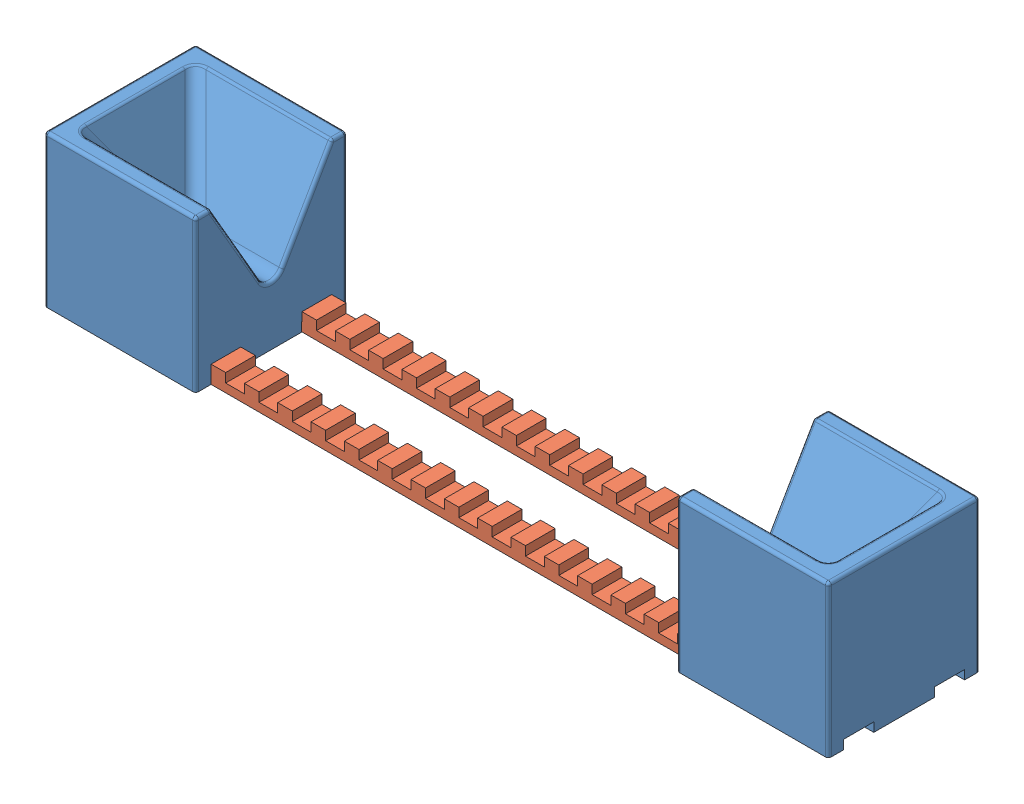
SolidWorks assembly Assem1, configuration Default. Lengths in mm.
Overall size (258.9 50 50).
4 component instances, 2 part files, 9 mates.
Components (placement in the parent):
- Chopstick_support1-1: Chopstick_support1 [Default] at origin size (50 50 50)
- Chopstick_support1-2: Chopstick_support1 [Default] at (258.9 0 0) x (-1 0 0) z (0 0 -1) size (50 50 50)
- Spacer-1: Spacer [Default] at (28 0 -19.9) x (0 0 1) z (-1 0 0) size (9.8 5.8 209)
- Spacer-2: Spacer [Default] at (28 0 10.1) x (0 0 1) z (-1 0 0) size (9.8 5.8 209)
Mates (geometry in assembly coordinates):
- Coincident4: coincident: plane of assembly through (0 0 0) normal (0 1 0); plane of Spacer-1 through (32.8 0 -10.1) normal (0 -1 0)
- Coincident5: coincident: plane of assembly through (0 0 0) normal (0 1 0); plane of Spacer-2 through (32.8 0 19.9) normal (0 -1 0)
- Coincident6: coincident: plane of Spacer-1 through (28 0 -10.1) normal (-1 0 0); plane of Chopstick_support1-1 through (28 6 20) normal (1 0 0)
- Coincident7: coincident: plane of Spacer-1 through (28 0 -10.1) normal (-1 0 0); plane of Spacer-2 through (28 0 19.9) normal (-1 0 0)
- Distance1: distance = 0.1 mm: plane of Chopstick_support1-1 through (50 3 20) normal (0 0 -1); plane of Spacer-2 through (28 0 19.9) normal (0 0 1)
- Distance2: distance = 0.1 mm: plane of Spacer-1 through (28 0 -19.9) normal (0 0 -1); plane of Chopstick_support1-1 through (50 3 -20) normal (0 0 1)
- Distance3: distance = 0.1 mm: plane of Spacer-1 through (28 0 -19.9) normal (0 0 -1); plane of Chopstick_support1-2 through (208.9 3 -20) normal (0 0 1)
- Coincident12: coincident: plane of Chopstick_support1-2 through (269.9 0 0) normal (0 -1 0); plane of assembly through (0 0 0) normal (0 1 0)
- Distance4: distance = 0.1 mm: plane of Spacer-2 through (230.8 2.8 19.9) normal (1 0 0); plane of Chopstick_support1-2 through (230.9 6 20) normal (-1 0 0)
